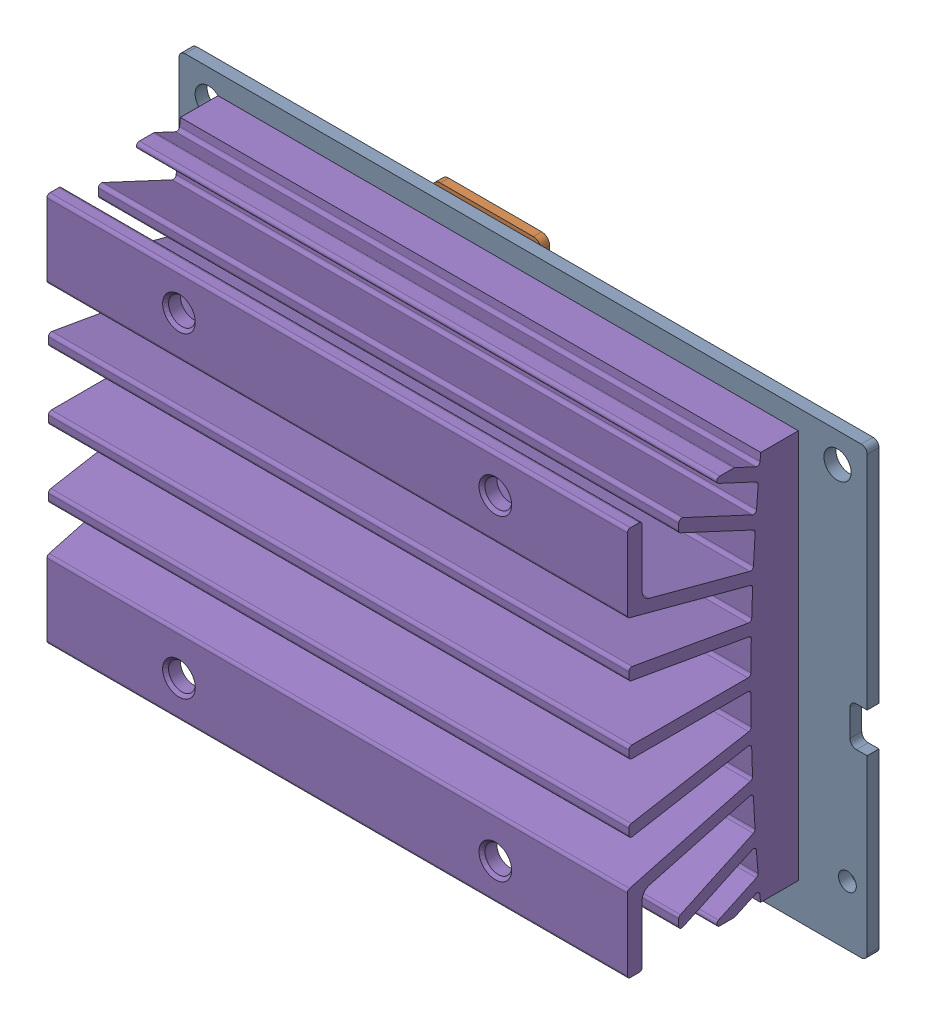
SolidWorks assembly 244-63448-0000-000_ASM, configuration Default. Lengths in mm.
Overall size (69.6 45 21.37).
13 component instances, 6 part files, 0 mates.
Components (placement in the parent):
- 142-63448-1GEN_A00-1: 142-63448-1GEN_A00 [Default] at origin size (69.6 45 1.2)
- 142-13448-1000-A02_ASM-1: 142-13448-1000-A02_ASM [Default] at origin size (23 37.02 4.04)
  - 080-0051-000_3-1: 080-0051-000_3 [Default] at (28.331 29.139 0) x (-1 0 0) z (0 0 -1) size (13.4 17 1.29)
  - TM670M-A2_1-1: TM670M-A2_1 [Default] at (23.7 13.45 1.2) size (23 23 1.31)
- 142-13448-1000-A02-SKU0000_ASM-1: 142-13448-1000-A02-SKU0000_ASM [Default] at origin size (23 23 1.31)
  - TM670M-A2_1-1: TM670M-A2_1 [Default] at (23.7 13.45 1.2) size (23 23 1.31)
- PORG_HSK_ASSY_ASM-1: PORG_HSK_ASSY_ASM [Default] at (0 0 4.01) size (58.7 39.4 17.3)
  - PORG_HEAT_SINK-1: PORG_HEAT_SINK [Default] at origin size (58.7 39.4 17.3)
- PORG_LEAF_SPRING_DRAWN-1: PORG_LEAF_SPRING_DRAWN [Default] at (0 0 -0.4) x (1 0.000001 0) z (0 0 1) size (39.83 21.3 1.2)
- PORG_LEAF_SPRING_SCREW-1: PORG_LEAF_SPRING_SCREW [Default] at (6.9871 5.9982 5.21) x (0 0 -1) z (0 1 0) size (6.41 4.7 4.7)
- PORG_LEAF_SPRING_SCREW-2: PORG_LEAF_SPRING_SCREW [Default] at (6.9871 20.9018 5.21) x (0 0 -1) z (0 1 0) size (6.41 4.7 4.7)
- PORG_LEAF_SPRING_SCREW-3: PORG_LEAF_SPRING_SCREW [Default] at (40.4129 20.9018 5.21) x (0 0 -1) z (0 1 0) size (6.41 4.7 4.7)
- PORG_LEAF_SPRING_SCREW-4: PORG_LEAF_SPRING_SCREW [Default] at (40.4129 5.9982 5.21) x (0 0 -1) z (0 1 0) size (6.41 4.7 4.7)
